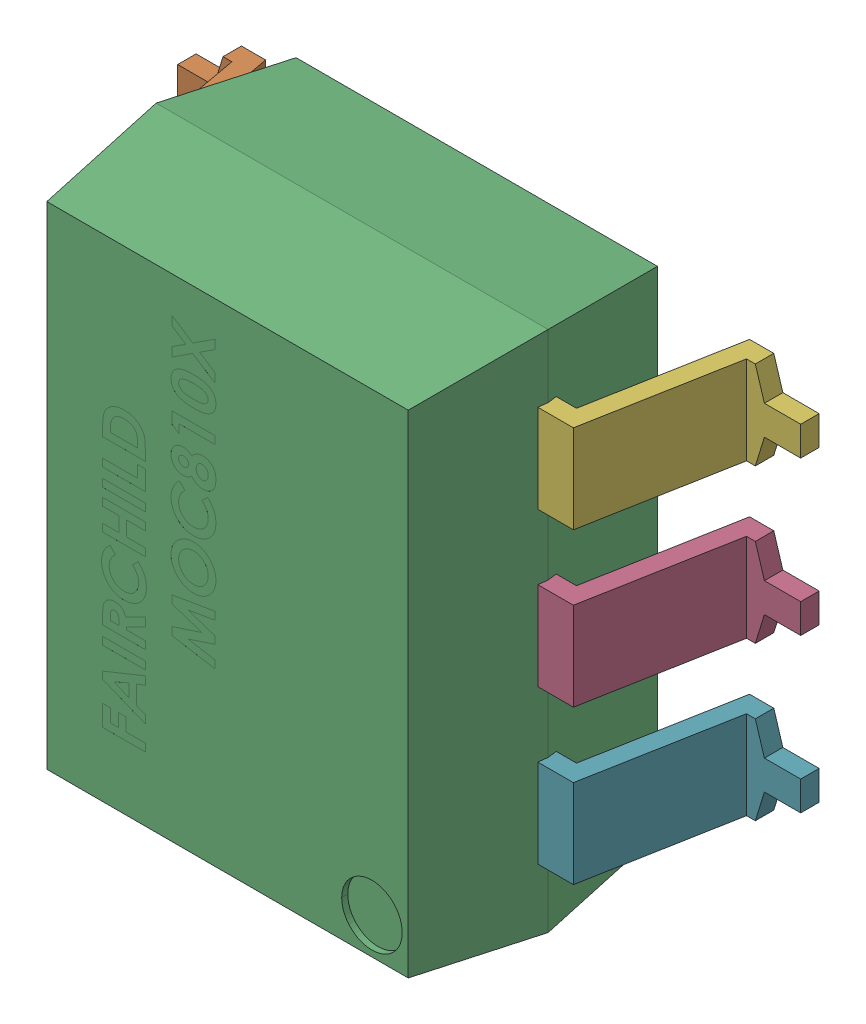
SolidWorks assembly U6_1.step, configuration Default. Lengths in mm.
Overall size (10.3 8.64 4.63).
8 component instances, 2 part files, 0 mates.
Components (placement in the parent):
- SMD DIP-6_1.step-11: SMD DIP-6_1.step [Default] at (401.3199 313.1819 2.5654) x (0 1 0) z (1 0 0) size (8.63 4.63 10.3)
  - MOC810X_SOIC6_PIN_1.step-64: MOC810X_SOIC6_PIN_1.step [Default] at (2.5236 0.1223 -5.1276) x (-1 0 0) z (0 0 -1) size (1.46 2.72 2.11)
  - MOC810X_SOIC6_PIN_1.step-65: MOC810X_SOIC6_PIN_1.step [Default] at (5.0636 0.1223 -5.1276) x (-1 0 0) z (0 0 -1) size (1.46 2.72 2.11)
  - MOC810X_SOIC6_BODY_1.step-11: MOC810X_SOIC6_BODY_1.step [Default] at (-2.5239 -0.0302 1.3524) size (8.63 4.12 6.48)
  - MOC810X_SOIC6_PIN_1.step-66: MOC810X_SOIC6_PIN_1.step [Default] at (1.0636 0.1223 1.3524) size (1.46 2.72 2.11)
  - MOC810X_SOIC6_PIN_1.step-67: MOC810X_SOIC6_PIN_1.step [Default] at (-0.0164 0.1223 -5.1276) x (-1 0 0) z (0 0 -1) size (1.46 2.72 2.11)
  - MOC810X_SOIC6_PIN_1.step-68: MOC810X_SOIC6_PIN_1.step [Default] at (3.6036 0.1223 1.3524) size (1.46 2.72 2.11)
  - MOC810X_SOIC6_PIN_1.step-69: MOC810X_SOIC6_PIN_1.step [Default] at (-1.4764 0.1223 1.3524) size (1.46 2.72 2.11)
